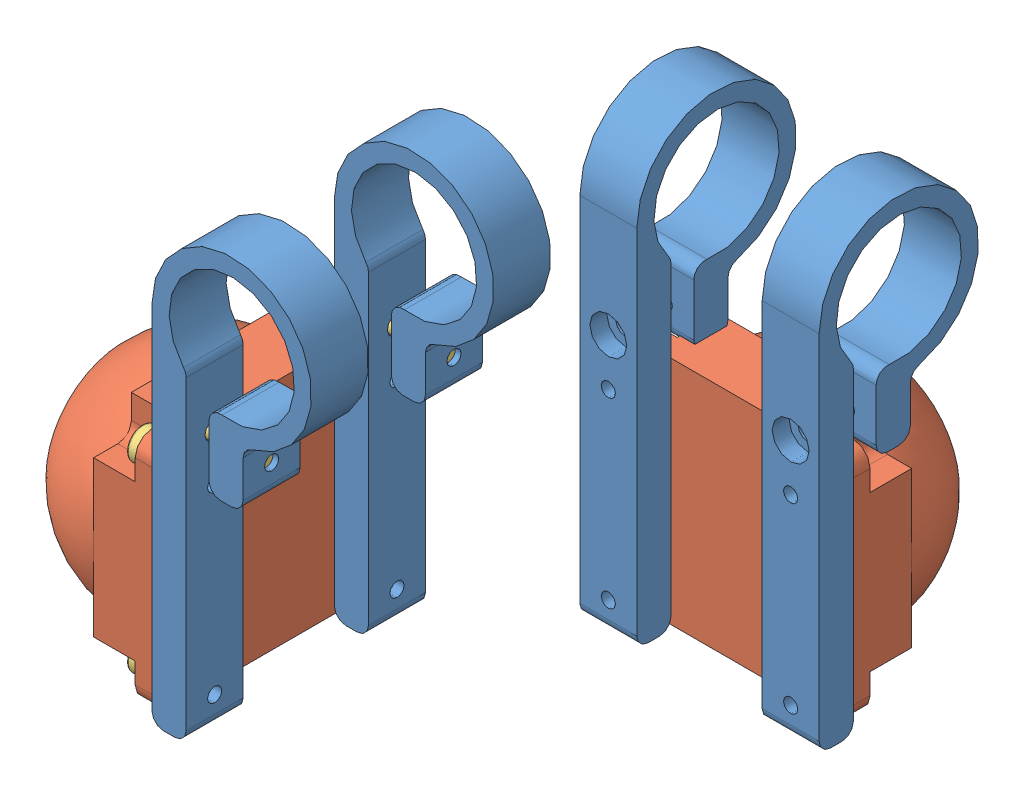
SolidWorks assembly joystick, configuration По умолчанию. Lengths in mm.
Overall size (140.13 128.97 42).
12 component instances, 3 part files, 24 mates.
Components (placement in the parent):
- joystick_holder-1: joystick_holder [По умолчанию] at (-38.2814 60.5852 -2.298) size (28 78 10)
- joystick_base-1: joystick_base [По умолчанию] at (-63.2814 17.5852 18.702) x (0 0 -1) z (1 0 0) size (40.5 40.5 26)
- socket head cap screw_din-2: socket head cap screw_din [DIN 912 M3 x 12 --- 12N] at (-52.2814 41.8392 2.702) size (15 5.5 5.5)
- socket head cap screw_din-3: socket head cap screw_din [DIN 912 M3 x 8 --- 8N] at (-58.9814 33.5852 2.702) size (11 5.5 5.5)
- socket head cap screw_din-4: socket head cap screw_din [DIN 912 M3 x 8 --- 8N] at (-58.9814 1.5852 2.702) size (11 5.5 5.5)
- joystick_holder-2: joystick_holder [По умолчанию] at (-38.2814 60.5852 29.702) size (28 78 10)
- socket head cap screw_din-5: socket head cap screw_din [DIN 912 M3 x 12 --- 12N] at (-52.2814 41.8392 34.702) size (15 5.5 5.5)
- socket head cap screw_din-6: socket head cap screw_din [DIN 912 M3 x 8 --- 8N] at (-58.9814 33.5852 34.702) size (11 5.5 5.5)
- socket head cap screw_din-7: socket head cap screw_din [DIN 912 M3 x 8 --- 8N] at (-58.9814 1.5852 34.702) size (11 5.5 5.5)
- joystick_base-2: joystick_base [По умолчанию] at (40.8531 68.5537 19.7499) size (40.5 40.5 26)
- joystick_holder-3: joystick_holder [По умолчанию] at (19.8531 111.5537 22.7499) x (0 0 -1) z (1 0 0) size (28 78 10)
- joystick_holder-4: joystick_holder [По умолчанию] at (51.8531 111.5537 22.7499) x (0 0 -1) z (1 0 0) size (28 78 10)
Mates (geometry in assembly coordinates):
- Совпадение1: coincident anti-aligned: plane of joystick_holder-1 through (-52.2814 60.5852 7.702) normal (-1 0 0); plane of joystick_base-1 through (-52.2814 17.5852 18.702) normal (1 0 0)
- Концентричный1: concentric anti-aligned: cylinder of joystick_holder-1 through (-52.2814 1.5852 2.702) axis (-1 0 0) radius 1.25; cylinder of joystick_base-1 through (-52.2814 1.5852 2.702) axis (1 0 0) radius 1.7
- Концентричный2: concentric anti-aligned: cylinder of joystick_holder-1 through (-52.2814 33.5852 2.702) axis (-1 0 0) radius 1.25; cylinder of joystick_base-1 through (-52.2814 33.5852 2.702) axis (1 0 0) radius 1.7
- Концентричный4: concentric aligned: cylinder of joystick_holder-1 through (-52.2814 41.8392 2.702) axis (-1 0 0) radius 1.7; cylinder of socket head cap screw_din-2 through (-84.0314 41.8392 2.702) axis (-1 0 0) radius 2.75
- Совпадение3: coincident anti-aligned: plane of joystick_holder-1 through (-49.2814 43.5392 2.702) normal (-1 0 0); plane of socket head cap screw_din-2 through (-49.2814 44.5892 2.702) normal (1 0 0)
- Концентричный5: concentric aligned: cylinder of joystick_base-1 through (-55.9814 33.5852 2.702) axis (-1 0 0) radius 2.3774; cylinder of socket head cap screw_din-3 through (-90.7314 33.5852 2.702) axis (-1 0 0) radius 2.75
- Совпадение4: coincident anti-aligned: plane of joystick_base-1 through (-55.9814 33.5852 2.702) normal (-1 0 0); plane of socket head cap screw_din-3 through (-55.9814 36.3352 2.702) normal (1 0 0)
- Концентричный6: concentric anti-aligned: cylinder of joystick_base-1 through (-52.2814 1.5852 2.702) axis (1 0 0) radius 1.7; cylinder of socket head cap screw_din-4 through (-90.7314 1.5852 2.702) axis (-1 0 0) radius 2.75
- Совпадение5: coincident anti-aligned: plane of joystick_base-1 through (-55.9814 1.5852 2.702) normal (-1 0 0); plane of socket head cap screw_din-4 through (-55.9814 4.3352 2.702) normal (1 0 0)
- Концентричный7: concentric anti-aligned: cylinder of joystick_base-1 through (-52.2814 1.5852 34.702) axis (1 0 0) radius 1.7; cylinder of joystick_holder-2 through (-52.2814 1.5852 34.702) axis (-1 0 0) radius 1.25
- Концентричный8: concentric anti-aligned: cylinder of joystick_base-1 through (-52.2814 33.5852 34.702) axis (1 0 0) radius 1.7; cylinder of joystick_holder-2 through (-52.2814 33.5852 34.702) axis (-1 0 0) radius 1.25
- Совпадение6: coincident anti-aligned: plane of joystick_base-1 through (-52.2814 17.5852 18.702) normal (1 0 0); plane of joystick_holder-2 through (-52.2814 60.5852 39.702) normal (-1 0 0)
- Совпадение7: coincident anti-aligned: plane of joystick_holder-1 through (-49.2814 43.5392 2.702) normal (-1 0 0); plane of socket head cap screw_din-5 through (-49.2814 44.5892 34.702) normal (1 0 0)
- Концентричный9: concentric aligned: cylinder of joystick_holder-2 through (-52.2814 41.8392 34.702) axis (-1 0 0) radius 1.7; cylinder of socket head cap screw_din-5 through (-84.0314 41.8392 34.702) axis (-1 0 0) radius 2.75
- Совпадение8: coincident anti-aligned: plane of joystick_base-1 through (-55.9814 33.5852 2.702) normal (-1 0 0); plane of socket head cap screw_din-6 through (-55.9814 36.3352 34.702) normal (1 0 0)
- Концентричный10: concentric anti-aligned: cylinder of joystick_base-1 through (-52.2814 33.5852 34.702) axis (1 0 0) radius 1.7; cylinder of socket head cap screw_din-6 through (-90.7314 33.5852 34.702) axis (-1 0 0) radius 2.75
- Концентричный11: concentric anti-aligned: cylinder of joystick_base-1 through (-52.2814 1.5852 34.702) axis (1 0 0) radius 1.7; cylinder of socket head cap screw_din-7 through (-90.7314 1.5852 34.702) axis (-1 0 0) radius 2.75
- Совпадение9: coincident anti-aligned: plane of joystick_base-1 through (-55.9814 33.5852 2.702) normal (-1 0 0); plane of socket head cap screw_din-7 through (-55.9814 4.3352 34.702) normal (1 0 0)
- Совпадение10: coincident: plane of joystick_base-2 through (40.8531 68.5537 30.7499) normal (0 0 1); plane of joystick_holder-4 through (61.8531 104.0039 30.7499) normal (0 0 -1)
- Совпадение11: coincident: plane of joystick_base-2 through (40.8531 68.5537 30.7499) normal (0 0 1); plane of joystick_holder-3 through (29.8531 104.0039 30.7499) normal (0 0 -1)
- Концентричный12: concentric: cylinder of joystick_base-2 through (24.8531 52.5537 30.7499) axis (0 0 1) radius 1.7; cylinder of joystick_holder-3 through (24.8531 52.5537 36.7499) axis (0 0 1) radius 1.25
- Концентричный13: concentric aligned: cylinder of joystick_base-2 through (24.8531 84.5537 30.7499) axis (0 0 1) radius 1.7; cylinder of joystick_holder-3 through (24.8531 84.5537 36.7499) axis (0 0 1) radius 1.25
- Концентричный14: concentric: cylinder of joystick_base-2 through (56.8531 52.5537 30.7499) axis (0 0 1) radius 1.7; cylinder of joystick_holder-4 through (56.8531 52.5537 36.7499) axis (0 0 1) radius 1.25
- Концентричный15: concentric aligned: cylinder of joystick_base-2 through (56.8531 84.5537 30.7499) axis (0 0 1) radius 1.7; cylinder of joystick_holder-4 through (56.8531 84.5537 36.7499) axis (0 0 1) radius 1.25
